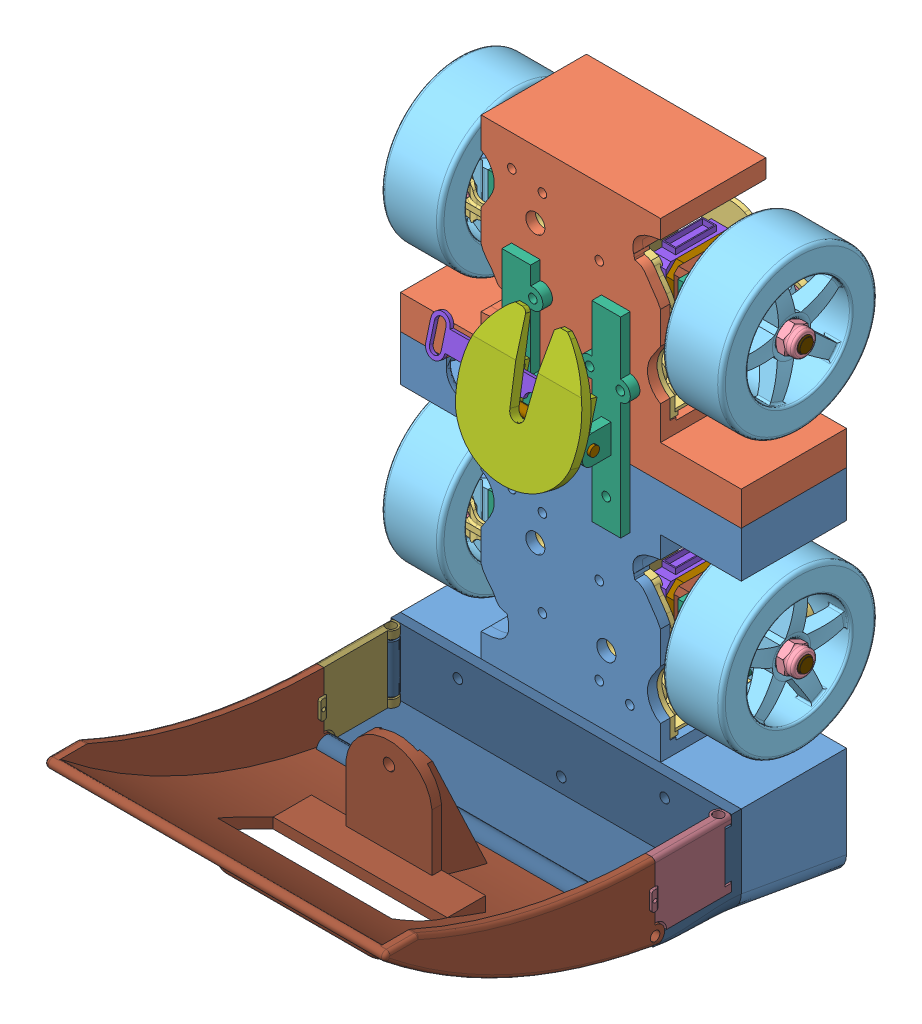
SolidWorks assembly Chassis assembly 2, configuration Default. Lengths in mm.
Overall size (185.37 311.7 273.69).
160 component instances, 31 part files, 34 mates.
Components (placement in the parent):
- Dolly chassis half 1-1: Dolly chassis half 1 [Default] at (2.6348 264.5467 189.9496) size (178 185.55 55.53)
- Dolly chassis half 2-1: Dolly chassis half 2 [Default] at (2.6348 264.5467 189.9496) size (178 119.39 55.45)
- Module Assembly-1: Module Assembly [Default] at (-63.8652 93.3967 162.4496) x (0 -1 0) z (-1 0 0) size (68.25 51.28 97.81)
  - Housing-1: Housing [Default] at origin size (64.25 48.5 67.91)
  - Bearing 12x8-1: Bearing 12x8 [Default] at (0 -18.25 0.75) x (-0.914388 0 0.40484) z (-0.40484 0 -0.914388) size (12 3.5 12)
  - Spindle-1: Spindle [Default] at (0 2 0.75) size (49.04 45 20.5)
  - Spindle base-1: Spindle base [Default] at (0 2 -15.25) x (-1 0 0) z (0 -1 0) size (37.62 3.5 44.8)
  - Encoder-1: Encoder [Défaut] at (0 2 -12.48) x (0 1 0) z (0 0 1) size (28.68 37.25 10.4)
  - Wheel-1: Wheel [Default] at (0 2 -8.55) x (0.929787 0.368098 0) z (0.368098 -0.929787 0) size (81.5 31 81.5) (hidden)
  - Stepper Nema14-1: Stepper Nema14 [Predeterminado] at (4.764 -15.5 -30.1157) x (-1 0 0) z (0 1 0) size (37.8 40 35)
    - nema14_base-1: nema14_base [Predeterminado] at (-12.736 -8.6343 35) size (37.8 9 35)
    - nema14_centro-1: nema14_centro [Predeterminado] at (-12.736 0.3657 35) size (35 4 35)
    - nema14_eje-1: nema14_eje [Predeterminado] at (4.764 -6.6343 17.5) x (0 1 0) z (-0.939004 0 0.343907) size (38 5 5)
    - nema14_techo-1: nema14_techo [Predeterminado] at (-12.736 4.3657 35) size (35 9 35)
  - Servo motor-1: Servo motor [Default] at (-25.7048 26.288 -66.0832) x (0 0 1) z (1 0 0) size (11.5 29.2 32.5) (flexible)
    - TowerPro-SG90-Body-1: TowerPro-SG90-Body [Default] at (13.6721 7.288 30.7048) size (11.5 26 32.5)
    - ServoFinalGear-1: ServoFinalGear [Default] at (13.6721 33.288 25.7048) x (0.607544 0 -0.794286) z (0.794286 0 0.607544) size (4.64 3.2 4.64)
  - Control arm-1: Control arm [Default] at (0 -7.5 -52.4111) x (0.891007 0 0.45399) z (0.45399 0 -0.891007) size (37.9 4.5 7.8)
  - Ball joint assy-1: Ball joint assy [Default] at (-26.7302 -5 -12.8697) x (-0.874356 0 0.485286) z (0.485286 0 0.874356) size (15.43 16.21 22.24) (flexible)
    - Ball-1: Ball [Default] at origin size (5.5 15.11 5.5)
    - Joint-1: Joint [Default] at (-3.8823 13.66 -6.9948) x (0.874356 0 -0.485286) z (0 -1 0) size (5.1 22.6 5.1)
  - Ball joint assy-2: Ball joint assy [Default] at (-26.7302 -5 -66.0308) x (-0.846813 0 0.531891) z (0.531891 0 0.846813) size (16.34 16.21 21.85) (flexible)
    - Ball-1: Ball [Default] at origin size (5.5 15.11 5.5)
    - Joint-1: Joint [Default] at (4.2551 13.66 6.7745) x (-0.846813 0 0.531891) z (0 -1 0) size (5.1 22.6 5.1)
  - Steering rod-1: Steering rod [Default] at (-26.7302 -18.66 -18.4608) x (-0.014502 0.999895 0) z (-0.999895 -0.014502 0) size (3 28.27 3)
  - Wheel adapter-1: Wheel adapter [Default] at (0 2 -13.8175) x (0.291296 -0.956633 0) z (-0.956633 -0.291296 0) size (8.34 40 8.37)
  - Wheel spacer-1: Wheel spacer [Default] at (0 2 12.25) x (0.368098 -0.929787 0) z (0.929787 0.368098 0) size (13.86 8 12)
  - M3x5 din 7984-1: M3x5 din 7984 [Default] at (15.31 20.9 -16.25) x (0.933505 0.358563 0) z (0 0 -1) size (5.5 5.5 7)
  - Housing lid-1: Housing lid [Default] at (0 4 0) x (-1 0 0) z (0 0 1) size (68.25 9.28 69.91)
  - Bearing 12x8-3: Bearing 12x8 [Default] at (0 22.25 0.75) x (-0.914388 0 0.40484) z (0.40484 0 0.914388) size (12 3.5 12)
  - M8 nut-1: M8 nut [Default] at (0 2 16.6825) x (-0.817347 -0.576146 0) z (0 0 1) size (13 16.06 8.5)
  - M3x5 din 7984-2: M3x5 din 7984 [Default] at (15.31 -16.9 -16.25) x (-0.933505 0.358563 0) z (0 0 -1) size (5.5 5.5 7)
  - M3x5 din 7984-3: M3x5 din 7984 [Default] at (-15.31 20.9 -16.25) x (0.933505 -0.358563 0) z (0 0 -1) size (5.5 5.5 7)
  - M3x5 din 7984-4: M3x5 din 7984 [Default] at (-15.31 -16.9 -16.25) x (-0.933505 -0.358563 0) z (0 0 -1) size (5.5 5.5 7)
  - M3x5 din 7984-5: M3x5 din 7984 [Default] at (-13 15 -17.75) x (0.999849 0.017374 0) z (0 0 1) size (5.5 5.5 7)
  - M3x5 din 7984-6: M3x5 din 7984 [Default] at (-13 -11 -17.75) x (-0.999849 0.017374 0) z (0 0 1) size (5.5 5.5 7)
  - M3x5 din 7984-7: M3x5 din 7984 [Default] at (13 15 -17.75) x (0.999849 -0.017374 0) z (0 0 1) size (5.5 5.5 7)
  - M3x5 din 7984-8: M3x5 din 7984 [Default] at (13 -11 -17.75) x (-0.999849 -0.017374 0) z (0 0 1) size (5.5 5.5 7)
- Module Assembly-2: Module Assembly [Default] at (69.1348 93.3967 162.4496) x (0 1 0) z (1 0 0) size (68.25 51.28 97.81)
  - Housing-1: Housing [Default] at origin size (64.25 48.5 67.91)
  - Bearing 12x8-1: Bearing 12x8 [Default] at (0 -18.25 0.75) x (-0.914388 0 0.40484) z (-0.40484 0 -0.914388) size (12 3.5 12)
  - Spindle-1: Spindle [Default] at (0 2 0.75) size (49.04 45 20.5)
  - Spindle base-1: Spindle base [Default] at (0 2 -15.25) x (-1 0 0) z (0 -1 0) size (37.62 3.5 44.8)
  - Encoder-1: Encoder [Défaut] at (0 2 -12.48) x (0 1 0) z (0 0 1) size (28.68 37.25 10.4)
  - Wheel-1: Wheel [Default] at (0 2 -8.55) x (0.929787 0.368098 0) z (0.368098 -0.929787 0) size (81.5 31 81.5) (hidden)
  - Stepper Nema14-1: Stepper Nema14 [Predeterminado] at (4.764 -15.5 -30.1157) x (-1 0 0) z (0 1 0) size (37.8 40 35)
    - nema14_base-1: nema14_base [Predeterminado] at (-12.736 -8.6343 35) size (37.8 9 35)
    - nema14_centro-1: nema14_centro [Predeterminado] at (-12.736 0.3657 35) size (35 4 35)
    - nema14_eje-1: nema14_eje [Predeterminado] at (4.764 -6.6343 17.5) x (0 1 0) z (-0.939004 0 0.343907) size (38 5 5)
    - nema14_techo-1: nema14_techo [Predeterminado] at (-12.736 4.3657 35) size (35 9 35)
  - Servo motor-1: Servo motor [Default] at (-25.7048 26.288 -66.0832) x (0 0 1) z (1 0 0) size (11.5 29.2 32.5) (flexible)
    - TowerPro-SG90-Body-1: TowerPro-SG90-Body [Default] at (13.6721 7.288 30.7048) size (11.5 26 32.5)
    - ServoFinalGear-1: ServoFinalGear [Default] at (13.6721 33.288 25.7048) x (0.607544 0 -0.794286) z (0.794286 0 0.607544) size (4.64 3.2 4.64)
  - Control arm-1: Control arm [Default] at (0 -7.5 -52.4111) x (0.891007 0 0.45399) z (0.45399 0 -0.891007) size (37.9 4.5 7.8)
  - Ball joint assy-1: Ball joint assy [Default] at (-26.7302 -5 -12.8697) x (-0.874356 0 0.485286) z (0.485286 0 0.874356) size (15.43 16.21 22.24) (flexible)
    - Ball-1: Ball [Default] at origin size (5.5 15.11 5.5)
    - Joint-1: Joint [Default] at (-3.8823 13.66 -6.9948) x (0.874356 0 -0.485286) z (0 -1 0) size (5.1 22.6 5.1)
  - Ball joint assy-2: Ball joint assy [Default] at (-26.7302 -5 -66.0308) x (-0.846813 0 0.531891) z (0.531891 0 0.846813) size (16.34 16.21 21.85) (flexible)
    - Ball-1: Ball [Default] at origin size (5.5 15.11 5.5)
    - Joint-1: Joint [Default] at (4.2551 13.66 6.7745) x (-0.846813 0 0.531891) z (0 -1 0) size (5.1 22.6 5.1)
  - Steering rod-1: Steering rod [Default] at (-26.7302 -18.66 -18.4608) x (-0.014502 0.999895 0) z (-0.999895 -0.014502 0) size (3 28.27 3)
  - Wheel adapter-1: Wheel adapter [Default] at (0 2 -13.8175) x (0.291296 -0.956633 0) z (-0.956633 -0.291296 0) size (8.34 40 8.37)
  - Wheel spacer-1: Wheel spacer [Default] at (0 2 12.25) x (0.368098 -0.929787 0) z (0.929787 0.368098 0) size (13.86 8 12)
  - M3x5 din 7984-1: M3x5 din 7984 [Default] at (15.31 20.9 -16.25) x (0.933505 0.358563 0) z (0 0 -1) size (5.5 5.5 7)
  - Housing lid-1: Housing lid [Default] at (0 4 0) x (-1 0 0) z (0 0 1) size (68.25 9.28 69.91)
  - Bearing 12x8-3: Bearing 12x8 [Default] at (0 22.25 0.75) x (-0.914388 0 0.40484) z (0.40484 0 0.914388) size (12 3.5 12)
  - M8 nut-1: M8 nut [Default] at (0 2 16.6825) x (-0.817347 -0.576146 0) z (0 0 1) size (13 16.06 8.5)
  - M3x5 din 7984-2: M3x5 din 7984 [Default] at (15.31 -16.9 -16.25) x (-0.933505 0.358563 0) z (0 0 -1) size (5.5 5.5 7)
  - M3x5 din 7984-3: M3x5 din 7984 [Default] at (-15.31 20.9 -16.25) x (0.933505 -0.358563 0) z (0 0 -1) size (5.5 5.5 7)
  - M3x5 din 7984-4: M3x5 din 7984 [Default] at (-15.31 -16.9 -16.25) x (-0.933505 -0.358563 0) z (0 0 -1) size (5.5 5.5 7)
  - M3x5 din 7984-5: M3x5 din 7984 [Default] at (-13 15 -17.75) x (0.999849 0.017374 0) z (0 0 1) size (5.5 5.5 7)
  - M3x5 din 7984-6: M3x5 din 7984 [Default] at (-13 -11 -17.75) x (-0.999849 0.017374 0) z (0 0 1) size (5.5 5.5 7)
  - M3x5 din 7984-7: M3x5 din 7984 [Default] at (13 15 -17.75) x (0.999849 -0.017374 0) z (0 0 1) size (5.5 5.5 7)
  - M3x5 din 7984-8: M3x5 din 7984 [Default] at (13 -11 -17.75) x (-0.999849 -0.017374 0) z (0 0 1) size (5.5 5.5 7)
- Module Assembly-3: Module Assembly [Default] at (69.1348 238.0467 162.4496) x (0 1 0) z (1 0 0) size (68.25 51.28 97.81)
  - Housing-1: Housing [Default] at origin size (64.25 48.5 67.91)
  - Bearing 12x8-1: Bearing 12x8 [Default] at (0 -18.25 0.75) x (-0.914388 0 0.40484) z (-0.40484 0 -0.914388) size (12 3.5 12)
  - Spindle-1: Spindle [Default] at (0 2 0.75) size (49.04 45 20.5)
  - Spindle base-1: Spindle base [Default] at (0 2 -15.25) x (-1 0 0) z (0 -1 0) size (37.62 3.5 44.8)
  - Encoder-1: Encoder [Défaut] at (0 2 -12.48) x (0 1 0) z (0 0 1) size (28.68 37.25 10.4)
  - Wheel-1: Wheel [Default] at (0 2 -8.55) x (0.929787 0.368098 0) z (0.368098 -0.929787 0) size (81.5 31 81.5) (hidden)
  - Stepper Nema14-1: Stepper Nema14 [Predeterminado] at (4.764 -15.5 -30.1157) x (-1 0 0) z (0 1 0) size (37.8 40 35)
    - nema14_base-1: nema14_base [Predeterminado] at (-12.736 -8.6343 35) size (37.8 9 35)
    - nema14_centro-1: nema14_centro [Predeterminado] at (-12.736 0.3657 35) size (35 4 35)
    - nema14_eje-1: nema14_eje [Predeterminado] at (4.764 -6.6343 17.5) x (0 1 0) z (-0.939004 0 0.343907) size (38 5 5)
    - nema14_techo-1: nema14_techo [Predeterminado] at (-12.736 4.3657 35) size (35 9 35)
  - Servo motor-1: Servo motor [Default] at (-25.7048 26.288 -66.0832) x (0 0 1) z (1 0 0) size (11.5 29.2 32.5) (flexible)
    - TowerPro-SG90-Body-1: TowerPro-SG90-Body [Default] at (13.6721 7.288 30.7048) size (11.5 26 32.5)
    - ServoFinalGear-1: ServoFinalGear [Default] at (13.6721 33.288 25.7048) x (0.607544 0 -0.794286) z (0.794286 0 0.607544) size (4.64 3.2 4.64)
  - Control arm-1: Control arm [Default] at (0 -7.5 -52.4111) x (0.891007 0 0.45399) z (0.45399 0 -0.891007) size (37.9 4.5 7.8)
  - Ball joint assy-1: Ball joint assy [Default] at (-26.7302 -5 -12.8697) x (-0.874356 0 0.485286) z (0.485286 0 0.874356) size (15.43 16.21 22.24) (flexible)
    - Ball-1: Ball [Default] at origin size (5.5 15.11 5.5)
    - Joint-1: Joint [Default] at (-3.8823 13.66 -6.9948) x (0.874356 0 -0.485286) z (0 -1 0) size (5.1 22.6 5.1)
  - Ball joint assy-2: Ball joint assy [Default] at (-26.7302 -5 -66.0308) x (-0.846813 0 0.531891) z (0.531891 0 0.846813) size (16.34 16.21 21.85) (flexible)
    - Ball-1: Ball [Default] at origin size (5.5 15.11 5.5)
    - Joint-1: Joint [Default] at (4.2551 13.66 6.7745) x (-0.846813 0 0.531891) z (0 -1 0) size (5.1 22.6 5.1)
  - Steering rod-1: Steering rod [Default] at (-26.7302 -18.66 -18.4608) x (-0.014502 0.999895 0) z (-0.999895 -0.014502 0) size (3 28.27 3)
  - Wheel adapter-1: Wheel adapter [Default] at (0 2 -13.8175) x (0.291296 -0.956633 0) z (-0.956633 -0.291296 0) size (8.34 40 8.37)
  - Wheel spacer-1: Wheel spacer [Default] at (0 2 12.25) x (0.368098 -0.929787 0) z (0.929787 0.368098 0) size (13.86 8 12)
  - M3x5 din 7984-1: M3x5 din 7984 [Default] at (15.31 20.9 -16.25) x (0.933505 0.358563 0) z (0 0 -1) size (5.5 5.5 7)
  - Housing lid-1: Housing lid [Default] at (0 4 0) x (-1 0 0) z (0 0 1) size (68.25 9.28 69.91)
  - Bearing 12x8-3: Bearing 12x8 [Default] at (0 22.25 0.75) x (-0.914388 0 0.40484) z (0.40484 0 0.914388) size (12 3.5 12)
  - M8 nut-1: M8 nut [Default] at (0 2 16.6825) x (-0.817347 -0.576146 0) z (0 0 1) size (13 16.06 8.5)
  - M3x5 din 7984-2: M3x5 din 7984 [Default] at (15.31 -16.9 -16.25) x (-0.933505 0.358563 0) z (0 0 -1) size (5.5 5.5 7)
  - M3x5 din 7984-3: M3x5 din 7984 [Default] at (-15.31 20.9 -16.25) x (0.933505 -0.358563 0) z (0 0 -1) size (5.5 5.5 7)
  - M3x5 din 7984-4: M3x5 din 7984 [Default] at (-15.31 -16.9 -16.25) x (-0.933505 -0.358563 0) z (0 0 -1) size (5.5 5.5 7)
  - M3x5 din 7984-5: M3x5 din 7984 [Default] at (-13 15 -17.75) x (0.999849 0.017374 0) z (0 0 1) size (5.5 5.5 7)
  - M3x5 din 7984-6: M3x5 din 7984 [Default] at (-13 -11 -17.75) x (-0.999849 0.017374 0) z (0 0 1) size (5.5 5.5 7)
  - M3x5 din 7984-7: M3x5 din 7984 [Default] at (13 15 -17.75) x (0.999849 -0.017374 0) z (0 0 1) size (5.5 5.5 7)
  - M3x5 din 7984-8: M3x5 din 7984 [Default] at (13 -11 -17.75) x (-0.999849 -0.017374 0) z (0 0 1) size (5.5 5.5 7)
- Module Assembly-4: Module Assembly [Default] at (-63.8652 238.0467 162.4496) x (0 -1 0) z (-1 0 0) size (68.25 51.28 97.81)
  - Housing-1: Housing [Default] at origin size (64.25 48.5 67.91)
  - Bearing 12x8-1: Bearing 12x8 [Default] at (0 -18.25 0.75) x (-0.914388 0 0.40484) z (-0.40484 0 -0.914388) size (12 3.5 12)
  - Spindle-1: Spindle [Default] at (0 2 0.75) size (49.04 45 20.5)
  - Spindle base-1: Spindle base [Default] at (0 2 -15.25) x (-1 0 0) z (0 -1 0) size (37.62 3.5 44.8)
  - Encoder-1: Encoder [Défaut] at (0 2 -12.48) x (0 1 0) z (0 0 1) size (28.68 37.25 10.4)
  - Wheel-1: Wheel [Default] at (0 2 -8.55) x (0.929787 0.368098 0) z (0.368098 -0.929787 0) size (81.5 31 81.5) (hidden)
  - Stepper Nema14-1: Stepper Nema14 [Predeterminado] at (4.764 -15.5 -30.1157) x (-1 0 0) z (0 1 0) size (37.8 40 35)
    - nema14_base-1: nema14_base [Predeterminado] at (-12.736 -8.6343 35) size (37.8 9 35)
    - nema14_centro-1: nema14_centro [Predeterminado] at (-12.736 0.3657 35) size (35 4 35)
    - nema14_eje-1: nema14_eje [Predeterminado] at (4.764 -6.6343 17.5) x (0 1 0) z (-0.939004 0 0.343907) size (38 5 5)
    - nema14_techo-1: nema14_techo [Predeterminado] at (-12.736 4.3657 35) size (35 9 35)
  - Servo motor-1: Servo motor [Default] at (-25.7048 26.288 -66.0832) x (0 0 1) z (1 0 0) size (11.5 29.2 32.5) (flexible)
    - TowerPro-SG90-Body-1: TowerPro-SG90-Body [Default] at (13.6721 7.288 30.7048) size (11.5 26 32.5)
    - ServoFinalGear-1: ServoFinalGear [Default] at (13.6721 33.288 25.7048) x (0.607544 0 -0.794286) z (0.794286 0 0.607544) size (4.64 3.2 4.64)
  - Control arm-1: Control arm [Default] at (0 -7.5 -52.4111) x (0.891007 0 0.45399) z (0.45399 0 -0.891007) size (37.9 4.5 7.8)
  - Ball joint assy-1: Ball joint assy [Default] at (-26.7302 -5 -12.8697) x (-0.874356 0 0.485286) z (0.485286 0 0.874356) size (15.43 16.21 22.24) (flexible)
    - Ball-1: Ball [Default] at origin size (5.5 15.11 5.5)
    - Joint-1: Joint [Default] at (-3.8823 13.66 -6.9948) x (0.874356 0 -0.485286) z (0 -1 0) size (5.1 22.6 5.1)
  - Ball joint assy-2: Ball joint assy [Default] at (-26.7302 -5 -66.0308) x (-0.846813 0 0.531891) z (0.531891 0 0.846813) size (16.34 16.21 21.85) (flexible)
    - Ball-1: Ball [Default] at origin size (5.5 15.11 5.5)
    - Joint-1: Joint [Default] at (4.2551 13.66 6.7745) x (-0.846813 0 0.531891) z (0 -1 0) size (5.1 22.6 5.1)
  - Steering rod-1: Steering rod [Default] at (-26.7302 -18.66 -18.4608) x (-0.014502 0.999895 0) z (-0.999895 -0.014502 0) size (3 28.27 3)
  - Wheel adapter-1: Wheel adapter [Default] at (0 2 -13.8175) x (0.291296 -0.956633 0) z (-0.956633 -0.291296 0) size (8.34 40 8.37)
  - Wheel spacer-1: Wheel spacer [Default] at (0 2 12.25) x (0.368098 -0.929787 0) z (0.929787 0.368098 0) size (13.86 8 12)
  - M3x5 din 7984-1: M3x5 din 7984 [Default] at (15.31 20.9 -16.25) x (0.933505 0.358563 0) z (0 0 -1) size (5.5 5.5 7)
  - Housing lid-1: Housing lid [Default] at (0 4 0) x (-1 0 0) z (0 0 1) size (68.25 9.28 69.91)
  - Bearing 12x8-3: Bearing 12x8 [Default] at (0 22.25 0.75) x (-0.914388 0 0.40484) z (0.40484 0 0.914388) size (12 3.5 12)
  - M8 nut-1: M8 nut [Default] at (0 2 16.6825) x (-0.817347 -0.576146 0) z (0 0 1) size (13 16.06 8.5)
  - M3x5 din 7984-2: M3x5 din 7984 [Default] at (15.31 -16.9 -16.25) x (-0.933505 0.358563 0) z (0 0 -1) size (5.5 5.5 7)
  - M3x5 din 7984-3: M3x5 din 7984 [Default] at (-15.31 20.9 -16.25) x (0.933505 -0.358563 0) z (0 0 -1) size (5.5 5.5 7)
  - M3x5 din 7984-4: M3x5 din 7984 [Default] at (-15.31 -16.9 -16.25) x (-0.933505 -0.358563 0) z (0 0 -1) size (5.5 5.5 7)
  - M3x5 din 7984-5: M3x5 din 7984 [Default] at (-13 15 -17.75) x (0.999849 0.017374 0) z (0 0 1) size (5.5 5.5 7)
  - M3x5 din 7984-6: M3x5 din 7984 [Default] at (-13 -11 -17.75) x (-0.999849 0.017374 0) z (0 0 1) size (5.5 5.5 7)
  - M3x5 din 7984-7: M3x5 din 7984 [Default] at (13 15 -17.75) x (0.999849 -0.017374 0) z (0 0 1) size (5.5 5.5 7)
  - M3x5 din 7984-8: M3x5 din 7984 [Default] at (13 -11 -17.75) x (-0.999849 -0.017374 0) z (0 0 1) size (5.5 5.5 7)
- Wheel-1: Wheel [Default] at (60.5848 93.3967 164.4496) x (0 0.146111 0.989268) z (0 0.989268 -0.146111) size (81.5 31 81.5)
- Wheel-2: Wheel [Default] at (60.5848 238.0467 164.4496) x (0 0.783676 -0.62117) z (0 -0.62117 -0.783676) size (81.5 31 81.5)
- Wheel-3: Wheel [Default] at (-55.3152 238.0467 164.4496) x (0 -0.929787 0.368098) z (0 -0.368098 -0.929787) size (81.5 31 81.5)
- Wheel-4: Wheel [Default] at (-55.3152 93.3967 164.4496) x (0 -0.783676 -0.62117) z (0 0.62117 -0.783676) size (81.5 31 81.5)
- Fifth_wheel_assembly-1: Fifth_wheel_assembly [Default] at (26.7306 135.1631 149.1448) x (-1 0 0) z (0 1 0) size (90.59 41.74 100)
  - Fifth_wheel_mount-1: Fifth_wheel_mount [Default] at (-6.9031 48.3048 102.7348) size (67.09 20 100)
  - Fifth_wheel_disk-1: Fifth_wheel_disk [Default] at (-5.9031 71.3457 44.4932) x (1 0 0) z (0 -0.255937 0.966694) size (66.74 23.06 75.99)
  - Fifth_wheel_kingpin-1: Fifth_wheel_kingpin [Default] at (-1.4031 62.5809 65.8769) x (1 0 0) z (0 -0.255937 0.966694) size (80 2 20)
  - Fifth_wheel_axle-1: Fifth_wheel_axle [Default] at (51.5969 60.8048 45.2348) x (0 0.948415 -0.31703) z (1 0 0) size (5 5 55)
- front assembly 2-1: front assembly 2 [Default] at (-66.6874 152.8407 117.1017) x (1 0 0) z (0 -1 0) size (181 187.95 83.28) (flexible)
  - Foldable front base 2-1: Foldable front base 2 [Default] at (158.3211 77.8479 159.546) size (179.15 52.01 49.18)
  - foldable front flap 2-1: foldable front flap 2 [Default] at (69.3211 122.8479 151.0232) x (-1 0 0) z (0 0 -1) size (178.61 145.94 74.18)
  - Foldable front side flap right 2-1: Foldable front side flap right 2 [Default] at (-17.1789 86.3479 110.946) x (0 0 1) z (-1 0 0) size (35 43 8.5)
  - Foldable front side flap left 2-1: Foldable front side flap left 2 [Default] at (155.8211 86.3479 145.946) x (0 0 -1) z (1 0 0) size (35 43 8.5)
Mates (geometry in assembly coordinates):
- Coincident1: coincident: plane of Dolly chassis half 1-1 through (-44.2041 168.828 -11.5535) normal (0 1 0); plane of Dolly chassis half 2-1 through (-44.2041 168.828 -67.8767) normal (0 -1 0)
- Coincident2: coincident: plane of Dolly chassis half 1-1 through (2.6348 264.5467 194.9496) normal (0 0 1); plane of Dolly chassis half 2-1 through (2.6348 264.5467 194.9496) normal (0 0 1)
- Coincident3: coincident: plane of Dolly chassis half 1-1 through (49.4737 264.5467 194.9496) normal (1 0 0); plane of Dolly chassis half 2-1 through (49.4737 264.5467 194.9496) normal (1 0 0)
- Concentric1: concentric: cylinder of Dolly chassis half 1-1 through (-15.9041 108.4967 199.9496) axis (0 0 -1) radius 5; cylinder of Module Assembly-1/Housing lid-1 through (-15.9041 108.4967 179.9496) axis (0 0 1) radius 5
- Coincident4: coincident: plane of Dolly chassis half 1-1 through (2.6348 264.5467 189.9496) normal (0 0 -1); plane of Module Assembly-1/Housing lid-1 through (-63.8652 93.3967 189.9496) normal (0 0 1)
- Coincident5: coincident: plane of Dolly chassis half 1-1 through (-44.2041 264.5467 194.9496) normal (-1 0 0); plane of Module Assembly-1/Housing lid-1 through (-44.2041 93.3967 187.4496) normal (-1 0 0)
- Concentric2: concentric: cylinder of Dolly chassis half 1-1 through (21.1737 78.2967 199.9496) axis (0 0 -1) radius 5; cylinder of Module Assembly-2/Housing lid-1 through (21.1737 78.2967 179.9496) axis (0 0 1) radius 5
- Coincident6: coincident: plane of Dolly chassis half 1-1 through (49.4737 119.8967 194.9496) normal (1 0 0); plane of Module Assembly-2/Housing lid-1 through (49.4737 93.3967 187.4496) normal (1 0 0)
- Coincident7: coincident: plane of Dolly chassis half 1-1 through (2.6348 264.5467 189.9496) normal (0 0 -1); plane of Module Assembly-2/Housing lid-1 through (69.1348 93.3967 189.9496) normal (0 0 1)
- Concentric3: concentric: cylinder of Dolly chassis half 2-1 through (21.1737 222.9467 199.9496) axis (0 0 -1) radius 5; cylinder of Module Assembly-3/Housing lid-1 through (21.1737 222.9467 179.9496) axis (0 0 1) radius 5
- Coincident8: coincident: plane of Dolly chassis half 2-1 through (2.6348 264.5467 189.9496) normal (0 0 -1); plane of Module Assembly-3/Housing lid-1 through (69.1348 238.0467 189.9496) normal (0 0 1)
- Coincident9: coincident: plane of Dolly chassis half 2-1 through (49.4737 264.5467 194.9496) normal (1 0 0); plane of Module Assembly-3/Housing lid-1 through (49.4737 238.0467 187.4496) normal (1 0 0)
- Concentric4: concentric: cylinder of Dolly chassis half 2-1 through (-15.9041 253.1467 199.9496) axis (0 0 -1) radius 5; cylinder of Module Assembly-4/Housing lid-1 through (-15.9041 253.1467 179.9496) axis (0 0 1) radius 5
- Coincident10: coincident: plane of Dolly chassis half 2-1 through (-44.2041 264.5467 194.9496) normal (-1 0 0); plane of Module Assembly-4/Housing lid-1 through (-44.2041 238.0467 187.4496) normal (-1 0 0)
- Coincident11: coincident: plane of Dolly chassis half 1-1 through (2.6348 264.5467 189.9496) normal (0 0 -1); plane of Module Assembly-4/Housing lid-1 through (-63.8652 238.0467 189.9496) normal (0 0 1)
- Concentric5: concentric: cylinder of Module Assembly-2/Wheel adapter-1 through (55.3173 93.3967 164.4496) axis (-1 0 0) radius 4; cylinder of Wheel-1 through (60.5848 93.3967 164.4496) axis (1 0 0) radius 4
- Coincident15: coincident: plane of Module Assembly-2/Wheel spacer-1 through (73.3848 90.8464 170.8913) normal (0 0.146111 0.989268); plane of Wheel-1 through (81.3848 90.8464 170.8913) normal (0 -0.146111 -0.989268)
- Coincident16: coincident: plane of Module Assembly-2/Wheel spacer-1 through (81.3848 93.3967 164.4496) normal (1 0 0); plane of Wheel-1 through (81.3848 93.3967 164.4496) normal (-1 0 0)
- Concentric6: concentric: cylinder of Module Assembly-3/Wheel adapter-1 through (55.3173 238.0467 164.4496) axis (-1 0 0) radius 4; cylinder of Wheel-2 through (60.5848 238.0467 164.4496) axis (1 0 0) radius 4
- Coincident17: coincident: plane of Module Assembly-3/Wheel spacer-1 through (73.3848 235.4964 170.8913) normal (0 0.146111 0.989268); plane of Wheel-2 through (81.3848 235.4964 170.8913) normal (0 -0.146111 -0.989268)
- Coincident18: coincident: plane of Module Assembly-3/Wheel spacer-1 through (81.3848 238.0467 164.4496) normal (1 0 0); plane of Wheel-2 through (81.3848 238.0467 164.4496) normal (-1 0 0)
- Concentric7: concentric: cylinder of Module Assembly-4/Wheel adapter-1 through (-50.0477 238.0467 164.4496) axis (1 0 0) radius 4; cylinder of Wheel-3 through (-55.3152 238.0467 164.4496) axis (-1 0 0) radius 4
- Coincident19: coincident: plane of Module Assembly-4/Wheel spacer-1 through (-68.1152 240.5969 170.8913) normal (0 -0.146111 0.989268); plane of Wheel-3 through (-76.1152 240.5969 170.8913) normal (0 0.146111 -0.989268)
- Coincident20: coincident: plane of Module Assembly-4/Wheel spacer-1 through (-76.1152 238.0467 164.4496) normal (-1 0 0); plane of Wheel-3 through (-76.1152 238.0467 164.4496) normal (1 0 0)
- Concentric8: concentric: cylinder of Module Assembly-1/Wheel adapter-1 through (-50.0477 93.3967 164.4496) axis (1 0 0) radius 4; cylinder of Wheel-4 through (-55.3152 93.3967 164.4496) axis (-1 0 0) radius 4
- Coincident21: coincident: plane of Module Assembly-1/Wheel spacer-1 through (-68.1152 95.9469 170.8913) normal (0 -0.146111 0.989268); plane of Wheel-4 through (-76.1152 95.9469 170.8913) normal (0 0.146111 -0.989268)
- Coincident22: coincident: plane of Module Assembly-1/Wheel spacer-1 through (-76.1152 93.3967 164.4496) normal (-1 0 0); plane of Wheel-4 through (-76.1152 93.3967 164.4496) normal (1 0 0)
- Coincident23: coincident: plane of Dolly chassis half 2-1 through (2.6348 264.5467 194.9496) normal (0 0 1); plane of Fifth_wheel_assembly-1/Fifth_wheel_mount-1 through (33.6337 237.898 194.9496) normal (0 0 -1)
- Parallel2: parallel: plane of Dolly chassis half 2-1 through (2.6348 287.898 189.9496) normal (0 1 0); plane of Fifth_wheel_assembly-1/Fifth_wheel_mount-1 through (33.6337 237.898 199.9496) normal (0 1 0)
- Distance1: distance = 50 mm: plane of Fifth_wheel_assembly-1/Fifth_wheel_mount-1 through (33.6337 237.898 199.9496) normal (0 1 0); plane of Dolly chassis half 2-1 through (2.6348 287.898 189.9496) normal (0 1 0)
- Coincident24: coincident: plane of Dolly chassis half 1-1 through (2.6348 264.5467 194.9496) normal (0 0 1); plane of front assembly 2-1/Foldable front base 2-1 through (91.6337 -6.7054 194.9496) normal (0 0 -1)
- Coincident25: coincident: plane of Dolly chassis half 1-1 through (91.6337 264.5467 189.9496) normal (1 0 0); plane of front assembly 2-1/Foldable front base 2-1 through (91.6337 -6.7054 239.9496) normal (1 0 0)
- Coincident26: coincident: plane of Dolly chassis half 1-1 through (147.4822 -6.7054 194.9496) normal (0 -0.984808 0.173648); plane of front assembly 2-1/Foldable front base 2-1 through (91.6337 -6.7054 194.9496) normal (0 -0.984808 0.173648)
- Distance2: distance = 58 mm: plane of Fifth_wheel_assembly-1/Fifth_wheel_mount-1 through (33.6337 237.898 199.9496) normal (1 0 0); plane of Dolly chassis half 1-1 through (91.6337 264.5467 189.9496) normal (1 0 0)
